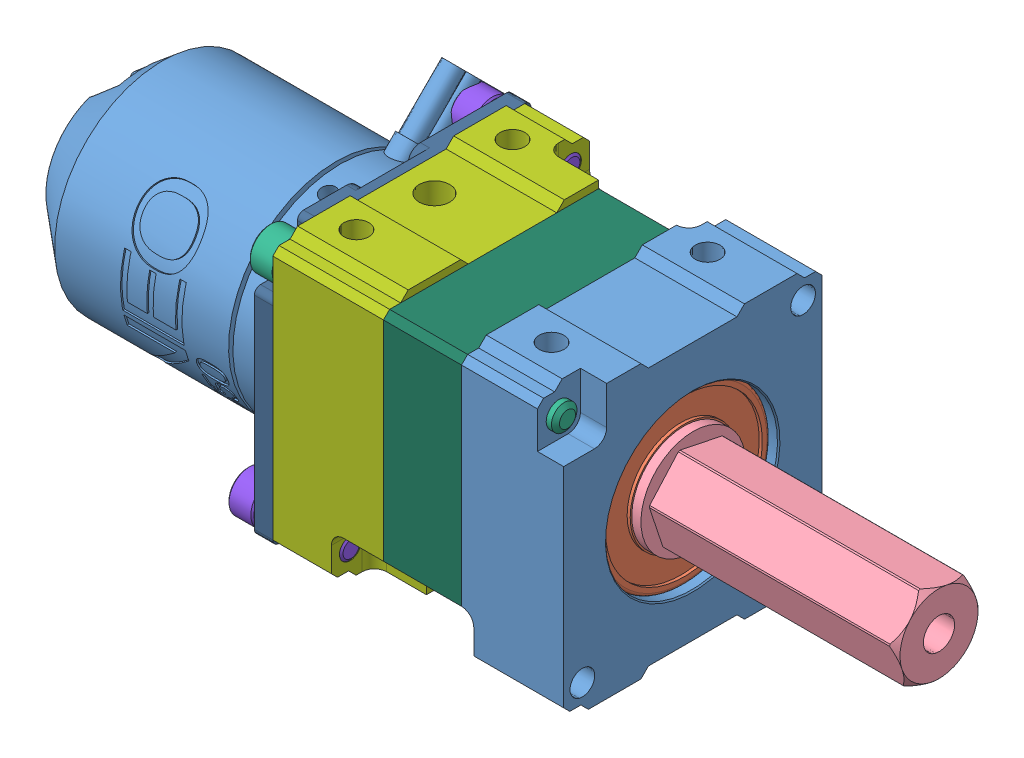
SolidWorks assembly versa+baby neo, configuration Default. Lengths in mm.
Overall size (134.9 49.81 50.15).
30 component instances, 19 part files, 2 mates.
Components (placement in the parent):
- VersaPlanetary_v2_Single_Stage_10_1_with_RS_550-1: VersaPlanetary_v2_Single_Stage_10_1_with_RS_550 [Default] at (0.0456 20.1036 152.4418) size (95.4 49.05 49.3) (flexible)
  - 217-2625-026 Rev1_1-1: 217-2625-026 Rev1_1 [Default] at (-6.5 22.225 0) x (0 -1 0) z (-1 0 0) size (44.45 42 18.13)
  - 217-2742-001 Rev4_1-1: 217-2742-001 Rev4_1 [Default] at (0.2002 22.225 0) x (1 0 0) z (0 -0.092627 0.995701) size (7 28 28)
  - 217-2742-001 Rev4_1-2: 217-2742-001 Rev4_1 [Default] at (8.2002 22.225 0) size (7 28 28)
  - 217-2625-017 Rev1_9714K61_1-1: 217-2625-017 Rev1_9714K61_1 [Default] at (7.42 22.3002 -0.342) x (0 0.56703 0.823697) z (0 -0.823697 0.56703) size (28.51 4.98 30.18)
  - 217-2625-003 Rev1_1-1: 217-2625-003 Rev1_1 [Default] at (6.9478 22.225 0) x (0 -0.979482 0.201533) z (1 0 0) size (17 17 64.12)
  - 217-2625-018 Rev1_98541A410_1-1: 217-2625-018 Rev1_98541A410_1 [Default] at (-0.7046 22.225 0) x (1 0 0) z (0 -0.017452 0.999848) size (1 19.6 17.4)
  - 832-1750-Ring-Gear-Screw_SSA0832-0500ZC_1-1: 832-1750-Ring-Gear-Screw_SSA0832-0500ZC_1 [Default] at (-30.7 4.725 -17.5) x (0 0.997447 0.071411) z (0 -0.071411 0.997447) size (6.73 48.51 6.73)
  - 832-1750-Ring-Gear-Screw_SSA0832-0500ZC_1-2: 832-1750-Ring-Gear-Screw_SSA0832-0500ZC_1 [Default] at (-30.7 39.725 17.5) x (0 0.005929 0.999982) z (0 -0.999982 0.005929) size (6.73 48.51 6.73)
  - 217-2625-025 Rev1_1-1: 217-2625-025 Rev1_1 [Default] at (-23.2 22.225 0) x (0 -1 0) z (-1 0 0) size (44.45 42 18)
  - 217-4649-002 Rev1_SSA0832-0500ZC_1-1: 217-4649-002 Rev1_SSA0832-0500ZC_1 [Default] at (-33.7 4.2645 17.9605) x (0 0.33842 -0.940995) z (0 0.940995 0.33842) size (6.73 16.76 6.73)
  - 217-4649-002 Rev1_SSA0832-0500ZC_1-2: 217-4649-002 Rev1_SSA0832-0500ZC_1 [Default] at (-33.7 40.1855 -17.9605) x (0 -0.308932 -0.951084) z (0 0.951084 -0.308932) size (6.73 16.76 6.73)
  - 217-4649-005 Rev1_SSA0003-008BA_1-1: 217-4649-005 Rev1_SSA0003-008BA_1 [Default] at (-30.7 22.225 -12.5) x (0 -0.5 0.866025) z (0 0.866025 0.5) size (5.5 11 5.5)
  - 217-4649-005 Rev1_SSA0003-008BA_1-2: 217-4649-005 Rev1_SSA0003-008BA_1 [Default] at (-30.7 22.225 12.5) x (0 -0.5 -0.866025) z (0 -0.866025 0.5) size (5.5 11 5.5)
  - 217-2822-001 Rev4_1-1: 217-2822-001 Rev4_1 [Default] at (-32.2 22.225 0) x (0 1 0) z (-1 0 0) size (42 42 4.8)
  - 217-2820 Rev1_Public_1-1: 217-2820 Rev1_Public_1 [Default] at (-4.6546 22.225 0) x (0 -0.456494 0.889726) z (-1 0 0) size (39.26 38.9 17.4)
    - 217-2625-100_1-1: 217-2625-100_1 [Default] at origin size (39.26 38.9 12.7)
      - 217-2625-008 Rev1_1-1: 217-2625-008 Rev1_1 [Default] at origin size (34.7 34.7 4.7)
      - 217-2625-010 Rev1_1-1: 217-2625-010 Rev1_1 [Default] at (0 10.193 3.65) x (0.999813 0.019336 0) z (0 0 1) size (4 4 12)
      - 217-2625-010 Rev1_1-2: 217-2625-010 Rev1_1 [Default] at (8.691 -5.3258 3.65) size (4 4 12)
      - 217-2625-010 Rev1_1-3: 217-2625-010 Rev1_1 [Default] at (-8.691 -5.3258 3.65) size (4 4 12)
      - 217-2625-005 Rev1_Planet_Revolving_Follower01_1-1: 217-2625-005 Rev1_Planet_Revolving_Follower01_1 [Default] at (8.691 -5.3258 6.35) x (0.932816 0.360354 0) z (0 0 1) size (16.91 16.92 8)
      - 217-2625-005 Rev1_Planet_Revolving_Follower01_1-2: 217-2625-005 Rev1_Planet_Revolving_Follower01_1 [Default] at (-8.691 -5.3258 6.35) x (-0.932788 -0.360426 0) z (0 0 1) size (16.91 16.92 8)
      - 217-2625-005 Rev1_Planet_Revolving_Follower01_1-3: 217-2625-005 Rev1_Planet_Revolving_Follower01_1 [Default] at (0 10.193 6.35) x (0.893583 0.448898 0) z (0 0 1) size (16.91 16.92 8)
    - 217-2625-007 Rev1_Public_1-1: 217-2625-007 Rev1_Public_1 [Default] at (0 0 6.7) x (0.992772 0.120019 0) z (0 0 1) size (14.49 14.49 12.72)
  - 217-2816-001 Rev1_1-1: 217-2816-001 Rev1_1 [Default] at (-6.35 22.225 0) x (0 -1 0) z (1 0 0) size (42 42 14.5)
  - 217-4649-001 Rev1_1-1: 217-4649-001 Rev1_1 [Default] at (-20.046 22.225 0) x (0 -1 0) z (1 0 0) size (18 18 13)
  - 217-4649-007 Rev1_94105A824_1-1: 217-4649-007 Rev1_94105A824_1 [Default] at (-25.521 22.225 -6.7835) x (-0.996104 -0.088191 0) z (0 0 -1) size (4.83 4.83 4.9)
  - 217-2625-012 Rev1_1-1: 217-2625-012 Rev1_1 [Default] at (-21.0318 22.225 0) x (0 0 1) z (-1 0 0) size (8.01 7.94 7.5)
- baby neo-2: baby neo [Default] at (-22.1544 42.3286 152.4418) x (-1 0 0) z (0 0 -1) size (56.01 42.91 43)
Mates (geometry in assembly coordinates):
- Concentric1: concentric anti-aligned: cylinder of VersaPlanetary_v2_Single_Stage_10_1_with_RS_550-1/217-2625-012 Rev1_1-1 through (-28.4862 42.3286 152.4418) axis (1 0 0) radius 1.5875; cylinder of baby neo-2 through (-78.1544 42.3286 152.4418) axis (-1 0 0) radius 1.585
- Coincident1: coincident anti-aligned: plane of VersaPlanetary_v2_Single_Stage_10_1_with_RS_550-1/217-2822-001 Rev4_1-1 through (-33.6544 42.3286 152.4418) normal (-1 0 0); plane of baby neo-2 through (-33.6544 48.8286 152.4418) normal (1 0 0)
